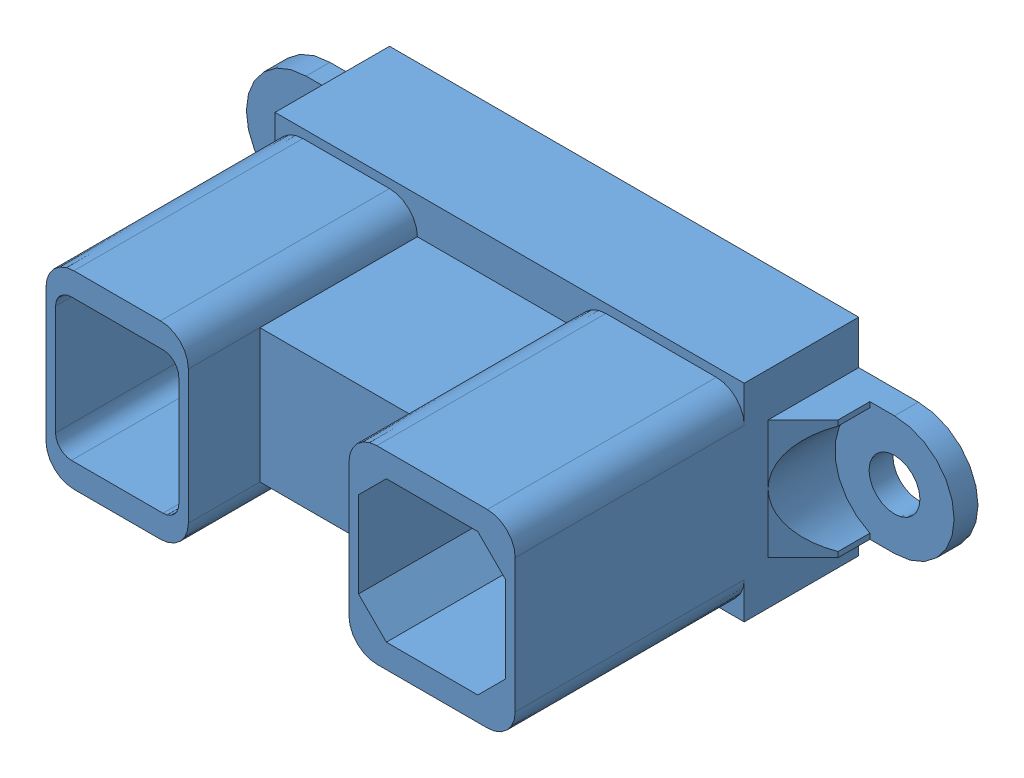
SolidWorks assembly ir_distance_sensor, configuration Default. Lengths in mm.
Overall size (44.5 17.75 21.6).
2 component instances, 2 part files, 3 mates.
Components (placement in the parent):
- ir_distance_sensor_body-1: ir_distance_sensor_body [Default] at (12.3744 23.2408 27.1941) size (44.5 17.75 21.6)
- 3-pin_JST_female-1: 3-pin_JST_female [Default] at (12.3744 11.9908 31.6941) x (1 0 0) z (0 -1 0) size (9.9 4.8 8.6)
Mates (geometry in assembly coordinates):
- Coincident1: coincident: plane of ir_distance_sensor_body-1 through (7.3244 11.9908 31.6941) normal (0 0 1); plane of 3-pin_JST_female-1 through (12.3744 11.9908 31.6941) normal (0 0 -1)
- Coincident2: coincident: plane of ir_distance_sensor_body-1 through (12.3744 11.9908 27.1941) normal (0 -1 0); plane of 3-pin_JST_female-1 through (12.3744 11.9908 36.4941) normal (0 -1 0)
- Width1: width: plane of ir_distance_sensor_body-1 through (17.4244 11.9908 30.4941) normal (1 0 0); plane of ir_distance_sensor_body-1 through (7.3244 11.9908 30.4941) normal (-1 0 0); plane of 3-pin_JST_female-1 through (17.3244 14.9908 34.0941) normal (1 0 0); plane of 3-pin_JST_female-1 through (7.4244 14.9908 34.0941) normal (-1 0 0)
